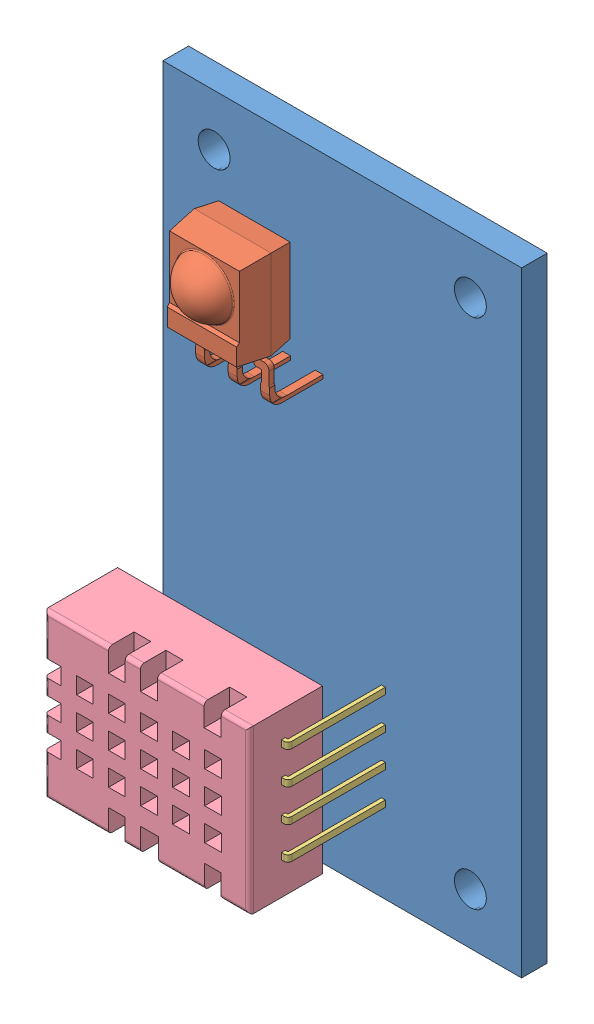
SolidWorks assembly Ensamblaje1, configuration Predeterminado. Lengths in mm.
Overall size (28 48 17.15).
5 component instances, 4 part files, 0 mates.
Components (placement in the parent):
- PCB-1: PCB [Predeterminado] at (-0.1873 5.95 -1) size (28 48 2)
- IRREC-1: IRREC [Predeterminado] at (-0.4752 25.9661 9.265) x (1 0 0) z (0 -1 0) size (6 8.11 10.7)
- DHT11-1: DHT11 [Predeterminado] at (-0.2773 -2.9766 10.4502) x (-1 0 0) z (0 0 1) size (16.5 12.7 10.1)
  - Array002-1: Array002 [Predeterminado] at origin size (0.5 8.12 7.6)
  - Cut-1: Cut [Predeterminado] at origin size (16 12.7 5.7)
